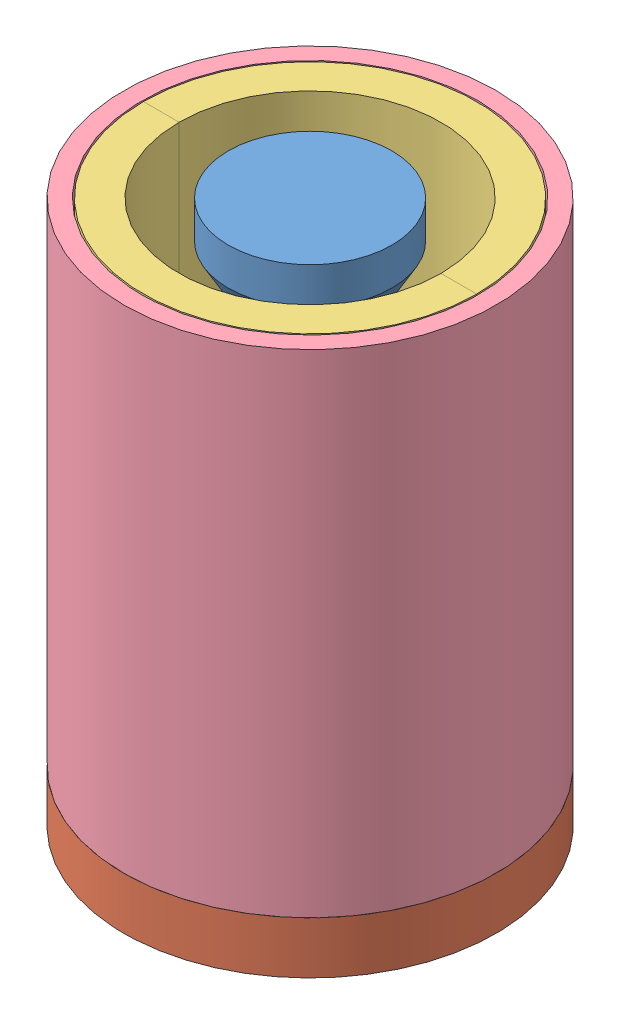
SolidWorks assembly Moule tuyère, configuration Défaut. Lengths in mm.
Overall size (50 73.12 50).
6 component instances, 4 part files, 16 mates.
Components (placement in the parent):
- Noyau-1: Noyau [Partie supérieure] at (0 -2.51 0) x (1 0 0) z (0 1 0) size (30.8 30.8 54)
- Noyau-2: Noyau [Partie inférieure] at (0 -2.51 0) x (-0.001444 0 -0.999999) z (0 1 0) size (21.97 21.97 21.9)
- Base-1: Base [Défaut] at (0 -40.06 0) size (50 7 50)
- Demi coque-1: Demi coque [Défaut] at (0 -1.5 0) size (44.8 69.12 22.4)
- Demi coque-2: Demi coque [Défaut] at (0 -1.5 0) x (-1 0 0) z (0 0 -1) size (44.8 69.12 22.4)
- Bride coque-1: Bride coque [Défaut] at origin size (50 66.12 50)
Mates (geometry in assembly coordinates):
- Coïncidente1: coincident anti-aligned: plane of Noyau-1 through (0 15.94 0) normal (0 1 0); plane of Noyau-2 through (0 15.94 0) normal (0 -1 0)
- Coïncidente2: coincident aligned: plane of Noyau-1 through (0 -2.51 0) normal (1 0 0)
- Parallèle1: parallel aligned: plane of Noyau-1 through (0 -2.51 0) normal (0 1 0)
- Coïncidente6: coincident aligned: plane of Noyau-1 through (0 -2.51 0) normal (1 0 0)
- Coïncidente7: coincident anti-aligned: plane of Noyau-1 through (0 -2.51 0) normal (0 0 -1)
- Coaxiale2: concentric aligned: cylinder of Noyau-1 through (0 33.04 0) axis (0 1 0) radius 15.4; cylinder of Base-1 through (0 -38.06 0) axis (0 1 0) radius 15.6
- Coïncidente8: coincident anti-aligned: plane of Noyau-1 through (0 -38.06 -15.4) normal (0 -1 0); plane of Base-1 through (0 -38.06 0) normal (0 1 0)
- Coïncidente9: coincident aligned: plane of Base-1 through (0 -40.06 0) normal (1 0 0)
- Coïncidente10: coincident aligned: plane of Demi coque-1 through (0 -1.5 0) normal (1 0 0)
- Coaxiale3: concentric anti-aligned: cylinder of Base-1 through (0 -36.06 0) axis (0 1 0) radius 17.4; cylinder of Demi coque-1 through (0 33.06 0) axis (0 -1 0) radius 22.4
- Coïncidente11: coincident anti-aligned: plane of Base-1 through (0 -36.06 0) normal (0 1 0); plane of Demi coque-1 through (0 -36.06 0) normal (0 -1 0)
- Coïncidente12: coincident aligned: plane of Bride coque-1 through (0 0 0) normal (1 0 0)
- Coïncidente13: coincident anti-aligned: plane of Base-1 through (0 -33.06 0) normal (0 1 0); plane of Bride coque-1 through (0 -33.06 0) normal (0 -1 0)
- Coaxiale4: concentric aligned: cylinder of Demi coque-1 through (0 33.06 0) axis (0 -1 0) radius 22.4; cylinder of Bride coque-1 through (0 33.06 0) axis (0 -1 0) radius 25
- Coïncidente14: coincident aligned: plane of Bride coque-1 through (0 0 0) normal (0 1 0)
- Coaxiale5: concentric aligned: cone of Noyau-1 through (0 10.94 0) axis (0 -1 0); cone of Noyau-2 through (0 11.14 0) axis (0 -1 0)
